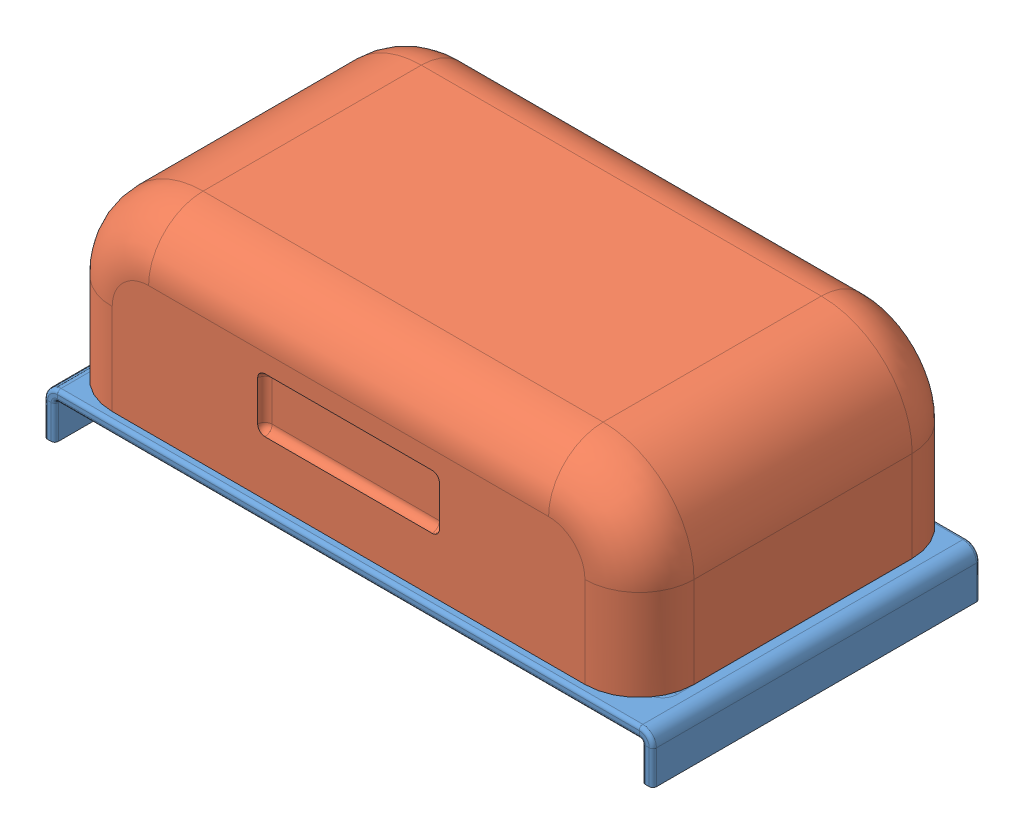
SolidWorks assembly assemblage 3mm, configuration Défaut. Lengths in mm.
Overall size (167.47 65.36 90.16).
2 component instances, 2 part files, 0 mates.
Components (placement in the parent):
- base tôle 4mm-1: base tôle 4mm [Défaut] at (24.9881 -24.1046 16.8266) size (167.47 17 90)
- couvercle 3mm-1: couvercle 3mm [Défaut] at (-37.358 -18.748 23.5502) size (160 50 90)
